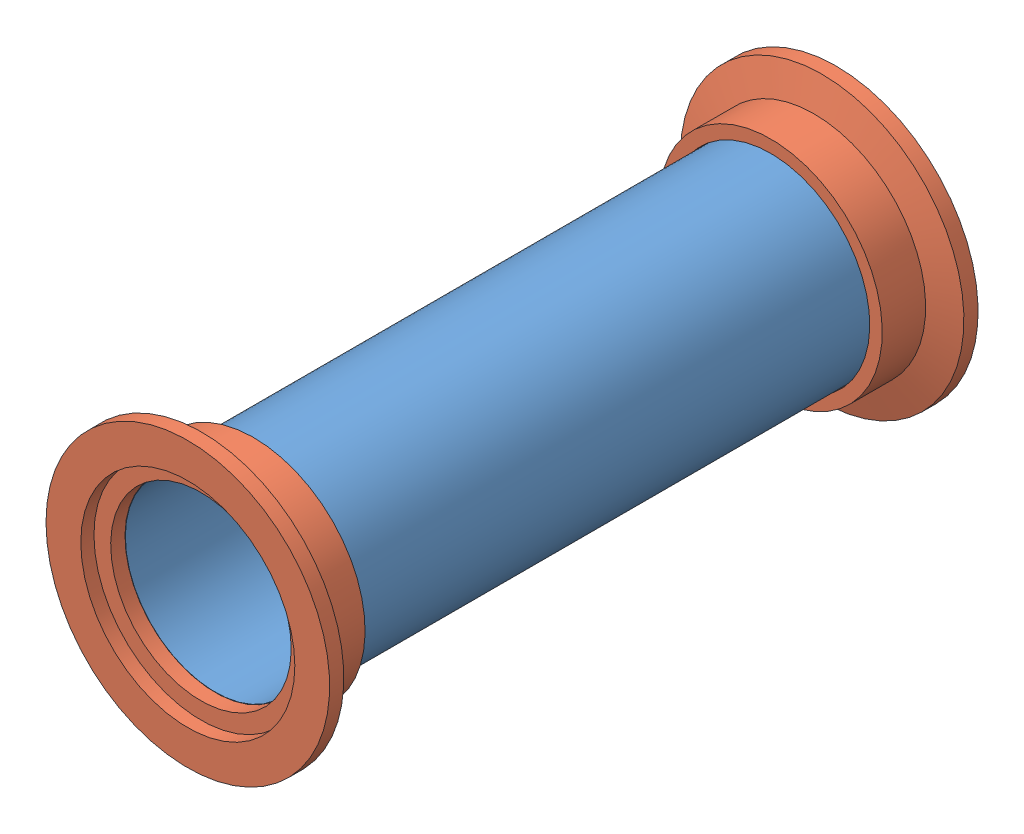
SolidWorks assembly 721002, configuration Default. Lengths in mm.
Overall size (75.3 75.3 125.43).
3 component instances, 2 part files, 4 mates.
Components (placement in the parent):
- 940202-1: 940202 [Default] at (45.6448 65.0054 25.7891) size (38.1 38.1 114.81)
- 713003-1: 713003 [Default] at (45.6448 65.0054 145.9057) x (0.978312 0.207136 0) z (0.207136 -0.978312 0) size (54.86 12.7 54.86)
- 713003-2: 713003 [Default] at (45.6448 65.0054 20.4805) x (-0.856646 -0.515904 0) z (0.515904 -0.856646 0) size (54.86 12.7 54.86)
Mates (geometry in assembly coordinates):
- Concentric1: concentric: cylinder of 940202-1 through (45.6448 65.0054 140.5971) axis (0 0 -1) radius 19.05; cylinder of 713003-1 through (45.6448 65.0054 145.9057) axis (0 0 1) radius 19.177
- Coincident1: coincident anti-aligned: plane of 940202-1 through (45.6448 65.0054 140.5971) normal (0 0 1); plane of 713003-1 through (64.4059 68.9776 140.5971) normal (0 0 -1)
- Concentric2: concentric: cylinder of 940202-1 through (45.6448 65.0054 140.5971) axis (0 0 -1) radius 19.05; cylinder of 713003-2 through (45.6448 65.0054 20.4805) axis (0 0 -1) radius 21.59
- Coincident2: coincident anti-aligned: plane of 940202-1 through (45.6448 65.0054 25.7891) normal (0 0 -1); plane of 713003-2 through (29.2169 55.1119 25.7891) normal (0 0 1)
